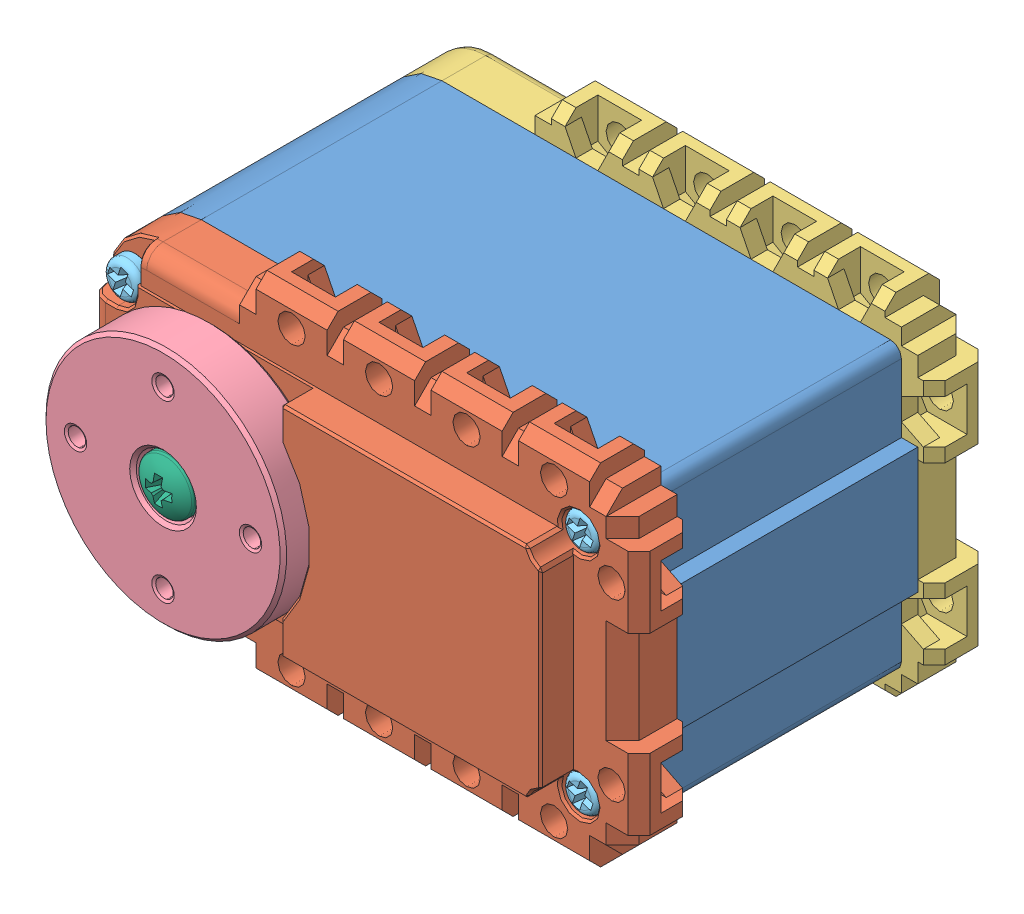
SolidWorks assembly AX-12A, configuration Default. Lengths in mm.
Overall size (50 32 40.55).
9 component instances, 6 part files, 19 mates.
Components (placement in the parent):
- AX-12A-01-1: AX-12A-01 [Default] at origin size (48.5 26 22)
- AX-12A-02-1: AX-12A-02 [Default] at (0 0 13.5) size (50 32 8)
- AX-12A-03-1: AX-12A-03 [Default] at (0 0 -13.5) x (1 0 0) z (0 0 -1) size (50 32 8)
- AX-12A-04-1: AX-12A-04 [Default] at (0 0 21) size (22 22 6.7)
- SetScrew-5: SetScrew [Default] at (33 10.4 14.5) x (0.31498 0.949098 0) z (0 0 -1) size (3.3 3.3 29.44)
- SetScrew-6: SetScrew [Default] at (-9 9.25 14.5) x (0.31498 0.949098 0) z (0 0 -1) size (3.3 3.3 29.44)
- SetScrew-7: SetScrew [Default] at (-9 -9.25 14.5) x (-0.958559 0.284893 0) z (0 0 -1) size (3.3 3.3 29.44)
- SetScrew-8: SetScrew [Default] at (33 -10.4 14.5) x (0.31498 0.949098 0) z (0 0 -1) size (3.3 3.3 29.44)
- pan head cross recess screw_iso-1: pan head cross recess screw_iso [ISO 7045 - M2.5 x 8 - Z --- 8C] at (0 0 21.6) x (0 0 -1) z (1 0 0) size (10.05 5 5)
Mates (geometry in assembly coordinates):
- Coincident1: coincident anti-aligned: plane of AX-12A-01-1 through (0 0 11) normal (0 0 1); plane of AX-12A-02-1 through (0 0 11) normal (0 0 -1)
- Coincident2: coincident aligned: plane of AX-12A-01-1 through (0 0 0) normal (1 0 0); plane of AX-12A-02-1 through (0 0 13.5) normal (1 0 0)
- Coincident3: coincident aligned: plane of AX-12A-01-1 through (0 0 0) normal (0 1 0); plane of AX-12A-02-1 through (0 0 13.5) normal (0 1 0)
- Coincident4: coincident anti-aligned: plane of AX-12A-01-1 through (0 0 -11) normal (0 0 -1); plane of AX-12A-03-1 through (0 0 -11) normal (0 0 1)
- Coincident5: coincident aligned: plane of AX-12A-01-1 through (0 0 0) normal (1 0 0); plane of AX-12A-03-1 through (0 0 -13.5) normal (1 0 0)
- Coincident6: coincident anti-aligned: plane of AX-12A-01-1 through (0 0 0) normal (0 1 0); plane of AX-12A-03-1 through (0 0 -13.5) normal (0 -1 0)
- Concentric1: concentric anti-aligned: cylinder of AX-12A-02-1 through (0 0 13.75) axis (0 0 1) radius 4.75; cylinder of AX-12A-04-1 through (0 0 21) axis (0 0 -1) radius 4.5
- Distance1: distance = 5 mm aligned: plane of AX-12A-02-1 through (0 0 16) normal (0 0 1); plane of AX-12A-04-1 through (0 2.75 21) normal (0 0 1)
- Coincident7: coincident aligned: plane of AX-12A-04-1 through (0 0 21) normal (1 0 0); plane of assembly through (0 0 0) normal (1 0 0)
- Concentric2: concentric aligned: cylinder of AX-12A-02-1 through (33 10.4 11) axis (0 0 1) radius 1; cylinder of SetScrew-5 through (33 10.4 14.5) axis (0 0 1) radius 0.85
- Coincident8: coincident anti-aligned: plane of AX-12A-02-1 through (0 0 14.5) normal (0 0 1); plane of SetScrew-5 through (33.8067 10.1323 14.5) normal (0 0 -1)
- Concentric3: concentric aligned: cylinder of AX-12A-02-1 through (-9 9.25 11) axis (0 0 1) radius 1; cylinder of SetScrew-6 through (-9 9.25 14.5) axis (0 0 1) radius 0.85
- Coincident9: coincident anti-aligned: plane of AX-12A-02-1 through (0 0 14.5) normal (0 0 1); plane of SetScrew-6 through (-8.1933 8.9823 14.5) normal (0 0 -1)
- Concentric4: concentric aligned: cylinder of AX-12A-02-1 through (-9 -9.25 11) axis (0 0 1) radius 1; cylinder of SetScrew-7 through (-9 -9.25 14.5) axis (0 0 1) radius 0.85
- Coincident10: coincident anti-aligned: plane of AX-12A-02-1 through (0 0 14.5) normal (0 0 1); plane of SetScrew-7 through (-8.7578 -8.4352 14.5) normal (0 0 -1)
- Concentric5: concentric aligned: cylinder of AX-12A-02-1 through (33 -10.4 11) axis (0 0 1) radius 1; cylinder of SetScrew-8 through (33 -10.4 14.5) axis (0 0 1) radius 0.85
- Coincident11: coincident anti-aligned: plane of AX-12A-02-1 through (0 0 14.5) normal (0 0 1); plane of SetScrew-8 through (33.8067 -10.6677 14.5) normal (0 0 -1)
- Concentric71: concentric anti-aligned: cylinder of AX-12A-04-1 through (0 0 21) axis (0 0 -1) radius 2.75; cylinder of pan head cross recess screw_iso-1 through (0 0 47) axis (0 0 1) radius 2.5
- Coincident131: coincident anti-aligned: plane of AX-12A-04-1 through (0 2.75 19.5) normal (0 0 1); plane of pan head cross recess screw_iso-1 through (0 1.25 19.5) normal (0 0 -1)
